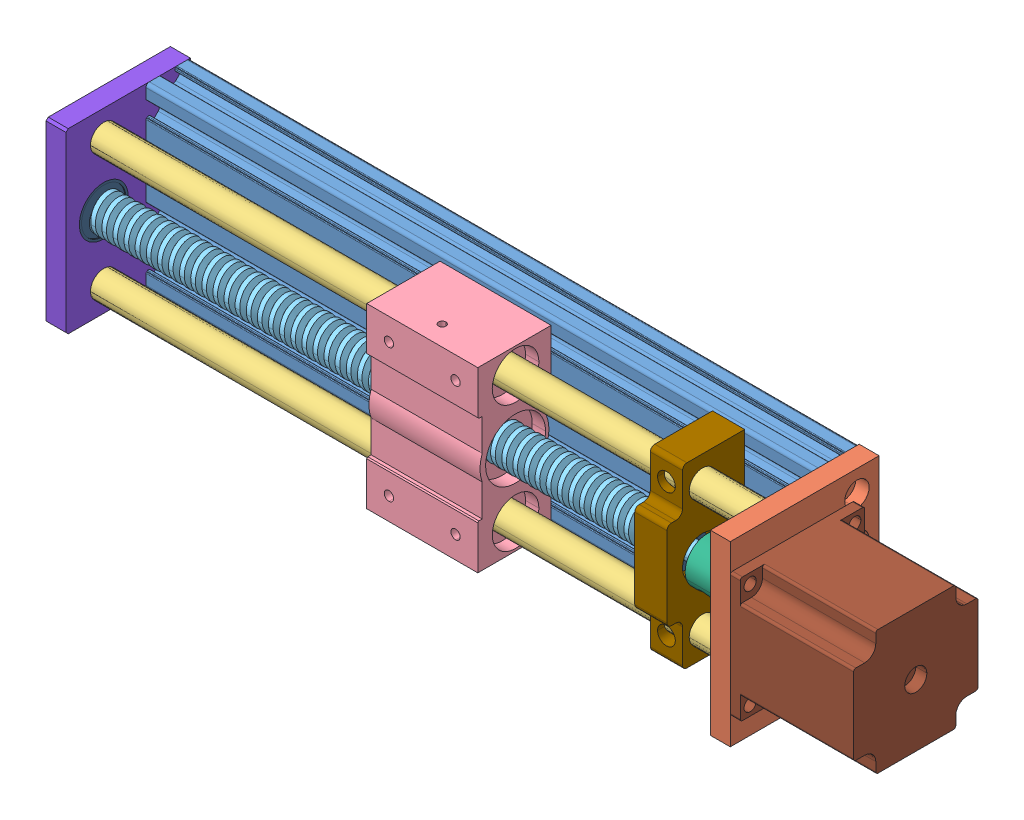
SolidWorks assembly 80双光轴行程200(2), configuration 默认. Lengths in mm.
Overall size (374.5 80 67).
19 component instances, 11 part files, 0 mates.
Components (placement in the parent):
- 80双光轴行程200(2).STEP-1: 80双光轴行程200(2).STEP [默认] at origin size (374.5 80 67)
  - 2080______200_______________.STEP-1: 2080______200_______________.STEP [默认] at (-89.5911 -5.5047 0) size (301 80 20)
  - ____________.STEP-1: ____________.STEP [默认] at (211.4089 -5.5047 23.5) x (0 1 0) z (1 0 0) size (80 67 9)
  - ____210mm.STEP-1: ____210mm.STEP [默认] at (-94.5911 -34.0047 29) x (0 0 -1) z (1 0 0) size (12 12 310)
  - ____210mm.STEP-2: ____210mm.STEP [默认] at (215.4089 22.9953 29) x (0 0 1) z (-1 0 0) size (12 12 310)
  - ____.STEP-1: ____.STEP [默认] at (70.7642 -5.5047 46) x (0 1 0) z (0 0 -1) size (80 50 33)
  - ______ ____16.STEP-1: ______ ____16.STEP [默认] at (-89.5911 -5.5047 29) x (0 -0.999429 -0.033801) z (0 -0.033801 0.999429) size (16.12 288 16)
  - ______.STEP-1: ______.STEP [默认] at (182.1101 -5.5047 29) x (0 -0.954169 -0.299267) z (0 -0.299267 0.954169) size (19.97 25 20)
  - ____-0.STEP-1: ____-0.STEP [默认] at (32.5698 24.4953 -6.55) x (0 1 0) z (0 0 1) size (11 10 5.3)
  - ____-0.STEP-2: ____-0.STEP [默认] at (-9.4326 -35.5047 -6.55) x (0 1 0) z (0 0 1) size (11 10 5.3)
  - ____-0.STEP-3: ____-0.STEP [默认] at (-49.5625 -35.5047 -6.55) x (0 1 0) z (0 0 1) size (11 10 5.3)
  - ____-0.STEP-4: ____-0.STEP [默认] at (30.7193 -35.5047 -6.55) x (0 1 0) z (0 0 1) size (11 10 5.3)
  - ____-0.STEP-5: ____-0.STEP [默认] at (-33.8317 24.4953 -6.55) x (0 1 0) z (0 0 1) size (11 10 5.3)
  - ____-0.STEP-6: ____-0.STEP [默认] at (64.9637 24.4953 -6.55) x (0 1 0) z (0 0 1) size (11 10 5.3)
  - __________.STEP-1: __________.STEP [默认] at (-98.5911 -5.5047 18) x (0 1 0) z (1 0 0) size (80 56 9)
  - __________-1.STEP-1: __________-1.STEP [默认] at (165.4089 -5.5047 27.5) x (0 1 0) z (1 0 0) size (80 35 14.5)
  - ____-2.STEP-1: ____-2.STEP [默认] at (-96.5911 -5.5047 29) x (0 0 -1) z (0 -1 0) size (22 7 22)
  - ____-2.STEP-2: ____-2.STEP [默认] at (172.4089 -5.5047 29) x (0 0 -1) z (0 1 0) size (22 7 22)
  - ______56mm.STEP-1: ______56mm.STEP [默认] at (224.9089 -5.5047 29) x (0 0 -1) z (1 0 0) size (56 56 78.5)
